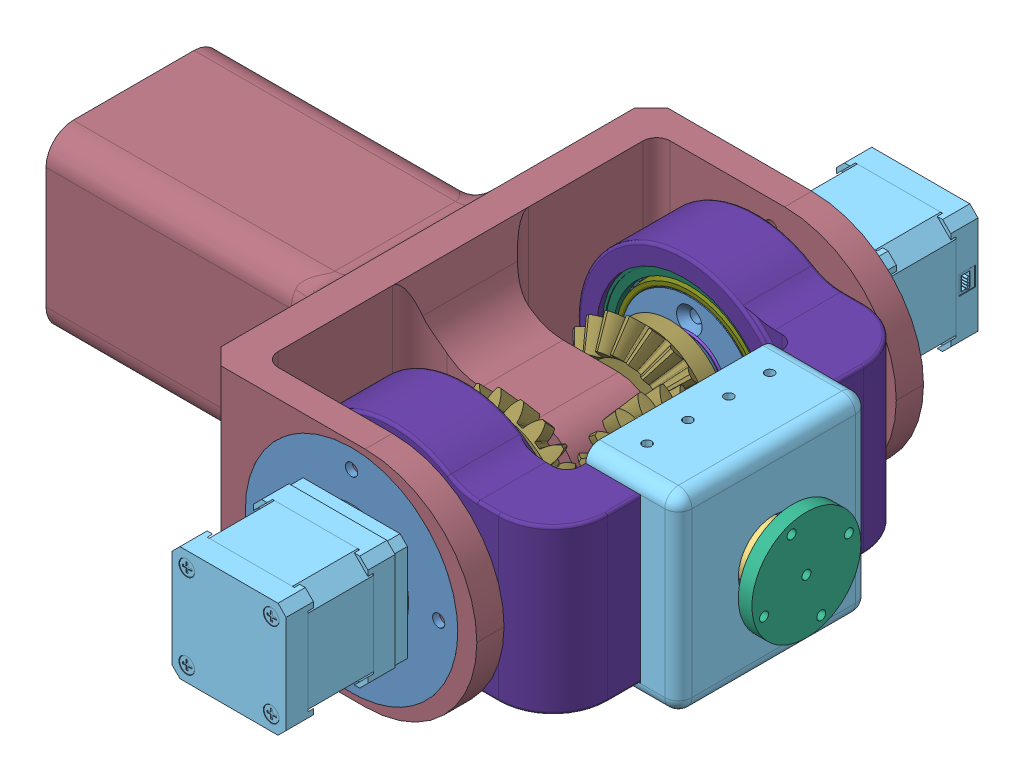
SolidWorks assembly Wrist assembly v3, configuration Default. Lengths in mm.
Overall size (247 82 254).
259 component instances, 28 part files, 61 mates.
Components (placement in the parent):
- Motor sleeve-1: Motor sleeve [Default] at (57.5488 50.2907 113.4481) x (0 0 -1) z (1 0 0) size (40 78 78)
- Motor sleeve-2: Motor sleeve [Default] at (57.5488 50.2907 -50.5519) x (0 0 1) z (-1 0 0) size (40 78 78)
- HK_1412-1: HK_1412 [Default] at (57.5488 50.2907 46.4481) x (0 0 -1) z (0.911021 -0.412359 0) size (12 20 20)
  - HK_1412_3-1: HK_1412_3 [Default] x (1 0 0) z (0 -0.382683 0.92388) size (7.3 2 2)
  - HK_1412_3-2: HK_1412_3 [Default] x (1 0 0) z (0 -0.707107 0.707107) size (7.3 2 2)
  - HK_1412_3-3: HK_1412_3 [Default] x (1 0 0) z (0 -0.92388 0.382683) size (7.3 2 2)
  - HK_1412_3-4: HK_1412_3 [Default] x (1 0 0) z (0 -1 0) size (7.3 2 2)
  - HK_1412_3-5: HK_1412_3 [Default] x (1 0 0) z (0 -0.92388 -0.382683) size (7.3 2 2)
  - HK_1412_3-6: HK_1412_3 [Default] x (1 0 0) z (0 -0.707107 -0.707107) size (7.3 2 2)
  - HK_1412_3-7: HK_1412_3 [Default] x (1 0 0) z (0 -0.382683 -0.92388) size (7.3 2 2)
  - HK_1412_3-8: HK_1412_3 [Default] x (1 0 0) z (0 0 -1) size (7.3 2 2)
  - HK_1412_3-9: HK_1412_3 [Default] x (1 0 0) z (0 0.382683 -0.92388) size (7.3 2 2)
  - HK_1412_3-10: HK_1412_3 [Default] x (1 0 0) z (0 0.707107 -0.707107) size (7.3 2 2)
  - HK_1412_3-11: HK_1412_3 [Default] x (1 0 0) z (0 0.92388 -0.382683) size (7.3 2 2)
  - HK_1412_3-12: HK_1412_3 [Default] x (1 0 0) z (0 1 0) size (7.3 2 2)
  - HK_1412_3-13: HK_1412_3 [Default] x (1 0 0) z (0 0.92388 0.382683) size (7.3 2 2)
  - HK_1412_3-14: HK_1412_3 [Default] x (1 0 0) z (0 0.707107 0.707107) size (7.3 2 2)
  - HK_1412_3-15: HK_1412_3 [Default] x (1 0 0) z (0 0.382683 0.92388) size (7.3 2 2)
  - HK_1412_3-16: HK_1412_3 [Default] at origin size (7.3 2 2)
  - HK_1412_20-1: HK_1412_20 [Default] x (1 0 0) z (0 -0.382683 0.92388) size (7.3 2 2)
  - HK_1412_20-2: HK_1412_20 [Default] x (1 0 0) z (0 -0.707107 0.707107) size (7.3 2 2)
  - HK_1412_20-3: HK_1412_20 [Default] x (1 0 0) z (0 -0.92388 0.382683) size (7.3 2 2)
  - HK_1412_20-4: HK_1412_20 [Default] x (1 0 0) z (0 -1 0) size (7.3 2 2)
  - HK_1412_20-5: HK_1412_20 [Default] x (1 0 0) z (0 -0.92388 -0.382683) size (7.3 2 2)
  - HK_1412_20-6: HK_1412_20 [Default] x (1 0 0) z (0 -0.707107 -0.707107) size (7.3 2 2)
  - HK_1412_20-7: HK_1412_20 [Default] x (1 0 0) z (0 -0.382683 -0.92388) size (7.3 2 2)
  - HK_1412_20-8: HK_1412_20 [Default] x (1 0 0) z (0 0 -1) size (7.3 2 2)
  - HK_1412_20-9: HK_1412_20 [Default] x (1 0 0) z (0 0.382683 -0.92388) size (7.3 2 2)
  - HK_1412_20-10: HK_1412_20 [Default] x (1 0 0) z (0 0.707107 -0.707107) size (7.3 2 2)
  - HK_1412_20-11: HK_1412_20 [Default] x (1 0 0) z (0 0.92388 -0.382683) size (7.3 2 2)
  - HK_1412_20-12: HK_1412_20 [Default] x (1 0 0) z (0 1 0) size (7.3 2 2)
  - HK_1412_20-13: HK_1412_20 [Default] x (1 0 0) z (0 0.92388 0.382683) size (7.3 2 2)
  - HK_1412_20-14: HK_1412_20 [Default] x (1 0 0) z (0 0.707107 0.707107) size (7.3 2 2)
  - HK_1412_20-15: HK_1412_20 [Default] x (1 0 0) z (0 0.382683 0.92388) size (7.3 2 2)
  - HK_1412_20-16: HK_1412_20 [Default] at origin size (7.3 2 2)
  - HK_1412_37-1: HK_1412_37 [Default] at origin size (12 20 20)
- HK_1412-2: HK_1412 [Default] at (57.5488 50.2907 28.4481) x (0 0 -1) z (0.122911 0.992418 0) size (12 20 20)
  - HK_1412_3-1: HK_1412_3 [Default] x (1 0 0) z (0 -0.382683 0.92388) size (7.3 2 2)
  - HK_1412_3-2: HK_1412_3 [Default] x (1 0 0) z (0 -0.707107 0.707107) size (7.3 2 2)
  - HK_1412_3-3: HK_1412_3 [Default] x (1 0 0) z (0 -0.92388 0.382683) size (7.3 2 2)
  - HK_1412_3-4: HK_1412_3 [Default] x (1 0 0) z (0 -1 0) size (7.3 2 2)
  - HK_1412_3-5: HK_1412_3 [Default] x (1 0 0) z (0 -0.92388 -0.382683) size (7.3 2 2)
  - HK_1412_3-6: HK_1412_3 [Default] x (1 0 0) z (0 -0.707107 -0.707107) size (7.3 2 2)
  - HK_1412_3-7: HK_1412_3 [Default] x (1 0 0) z (0 -0.382683 -0.92388) size (7.3 2 2)
  - HK_1412_3-8: HK_1412_3 [Default] x (1 0 0) z (0 0 -1) size (7.3 2 2)
  - HK_1412_3-9: HK_1412_3 [Default] x (1 0 0) z (0 0.382683 -0.92388) size (7.3 2 2)
  - HK_1412_3-10: HK_1412_3 [Default] x (1 0 0) z (0 0.707107 -0.707107) size (7.3 2 2)
  - HK_1412_3-11: HK_1412_3 [Default] x (1 0 0) z (0 0.92388 -0.382683) size (7.3 2 2)
  - HK_1412_3-12: HK_1412_3 [Default] x (1 0 0) z (0 1 0) size (7.3 2 2)
  - HK_1412_3-13: HK_1412_3 [Default] x (1 0 0) z (0 0.92388 0.382683) size (7.3 2 2)
  - HK_1412_3-14: HK_1412_3 [Default] x (1 0 0) z (0 0.707107 0.707107) size (7.3 2 2)
  - HK_1412_3-15: HK_1412_3 [Default] x (1 0 0) z (0 0.382683 0.92388) size (7.3 2 2)
  - HK_1412_3-16: HK_1412_3 [Default] at origin size (7.3 2 2)
  - HK_1412_20-1: HK_1412_20 [Default] x (1 0 0) z (0 -0.382683 0.92388) size (7.3 2 2)
  - HK_1412_20-2: HK_1412_20 [Default] x (1 0 0) z (0 -0.707107 0.707107) size (7.3 2 2)
  - HK_1412_20-3: HK_1412_20 [Default] x (1 0 0) z (0 -0.92388 0.382683) size (7.3 2 2)
  - HK_1412_20-4: HK_1412_20 [Default] x (1 0 0) z (0 -1 0) size (7.3 2 2)
  - HK_1412_20-5: HK_1412_20 [Default] x (1 0 0) z (0 -0.92388 -0.382683) size (7.3 2 2)
  - HK_1412_20-6: HK_1412_20 [Default] x (1 0 0) z (0 -0.707107 -0.707107) size (7.3 2 2)
  - HK_1412_20-7: HK_1412_20 [Default] x (1 0 0) z (0 -0.382683 -0.92388) size (7.3 2 2)
  - HK_1412_20-8: HK_1412_20 [Default] x (1 0 0) z (0 0 -1) size (7.3 2 2)
  - HK_1412_20-9: HK_1412_20 [Default] x (1 0 0) z (0 0.382683 -0.92388) size (7.3 2 2)
  - HK_1412_20-10: HK_1412_20 [Default] x (1 0 0) z (0 0.707107 -0.707107) size (7.3 2 2)
  - HK_1412_20-11: HK_1412_20 [Default] x (1 0 0) z (0 0.92388 -0.382683) size (7.3 2 2)
  - HK_1412_20-12: HK_1412_20 [Default] x (1 0 0) z (0 1 0) size (7.3 2 2)
  - HK_1412_20-13: HK_1412_20 [Default] x (1 0 0) z (0 0.92388 0.382683) size (7.3 2 2)
  - HK_1412_20-14: HK_1412_20 [Default] x (1 0 0) z (0 0.707107 0.707107) size (7.3 2 2)
  - HK_1412_20-15: HK_1412_20 [Default] x (1 0 0) z (0 0.382683 0.92388) size (7.3 2 2)
  - HK_1412_20-16: HK_1412_20 [Default] at origin size (7.3 2 2)
  - HK_1412_37-1: HK_1412_37 [Default] at origin size (12 20 20)
- 17HS15-1684D-HG10-AR3-2: 17HS15-1684D-HG10-AR3 [Default] at (57.5488 50.2907 -55.5519) size (42.88 42 103.5)
- 17HS15-1684D-HG10-AR3-3: 17HS15-1684D-HG10-AR3 [Default] at (57.5488 50.2907 118.4481) x (-1 0 0) z (0 0 -1) size (42.88 42 103.5)
- shaft-1: shaft [Default] at (57.5488 50.2907 -12.0519) x (0 0 1) z (0.017885 0.99984 0) size (42 17 17)
- shaft-2: shaft [Default] at (57.5488 50.2907 74.9481) x (0 0 -1) z (-0.597351 0.80198 0) size (42 17 17)
- AXK_1528___AS_1528___AS_1528-2: AXK_1528___AS_1528___AS_1528 [Default] at (57.5488 50.2907 71.4481) x (0 0 -1) z (0.812919 0.582377 0) size (4 28 28)
  - AXK_1528___AS_1528___AS_1528_3-1: AXK_1528___AS_1528___AS_1528_3 [Default] x (1 0 0) z (0 -0.309017 0.951057) size (2 5 2)
  - AXK_1528___AS_1528___AS_1528_3-2: AXK_1528___AS_1528___AS_1528_3 [Default] x (1 0 0) z (0 -0.587785 0.809017) size (2 5 2)
  - AXK_1528___AS_1528___AS_1528_3-3: AXK_1528___AS_1528___AS_1528_3 [Default] x (1 0 0) z (0 -0.809017 0.587785) size (2 5 2)
  - AXK_1528___AS_1528___AS_1528_3-4: AXK_1528___AS_1528___AS_1528_3 [Default] x (1 0 0) z (0 -0.951057 0.309017) size (2 5 2)
  - AXK_1528___AS_1528___AS_1528_3-5: AXK_1528___AS_1528___AS_1528_3 [Default] x (1 0 0) z (0 -1 0) size (2 5 2)
  - AXK_1528___AS_1528___AS_1528_3-6: AXK_1528___AS_1528___AS_1528_3 [Default] x (1 0 0) z (0 -0.951057 -0.309017) size (2 5 2)
  - AXK_1528___AS_1528___AS_1528_3-7: AXK_1528___AS_1528___AS_1528_3 [Default] x (1 0 0) z (0 -0.809017 -0.587785) size (2 5 2)
  - AXK_1528___AS_1528___AS_1528_3-8: AXK_1528___AS_1528___AS_1528_3 [Default] x (1 0 0) z (0 -0.587785 -0.809017) size (2 5 2)
  - AXK_1528___AS_1528___AS_1528_3-9: AXK_1528___AS_1528___AS_1528_3 [Default] x (1 0 0) z (0 -0.309017 -0.951057) size (2 5 2)
  - AXK_1528___AS_1528___AS_1528_3-10: AXK_1528___AS_1528___AS_1528_3 [Default] x (1 0 0) z (0 0 -1) size (2 5 2)
  - AXK_1528___AS_1528___AS_1528_3-11: AXK_1528___AS_1528___AS_1528_3 [Default] x (1 0 0) z (0 0.309017 -0.951057) size (2 5 2)
  - AXK_1528___AS_1528___AS_1528_3-12: AXK_1528___AS_1528___AS_1528_3 [Default] x (1 0 0) z (0 0.587785 -0.809017) size (2 5 2)
  - AXK_1528___AS_1528___AS_1528_3-13: AXK_1528___AS_1528___AS_1528_3 [Default] x (1 0 0) z (0 0.809017 -0.587785) size (2 5 2)
  - AXK_1528___AS_1528___AS_1528_3-14: AXK_1528___AS_1528___AS_1528_3 [Default] x (1 0 0) z (0 0.951057 -0.309017) size (2 5 2)
  - AXK_1528___AS_1528___AS_1528_3-15: AXK_1528___AS_1528___AS_1528_3 [Default] x (1 0 0) z (0 1 0) size (2 5 2)
  - AXK_1528___AS_1528___AS_1528_3-16: AXK_1528___AS_1528___AS_1528_3 [Default] x (1 0 0) z (0 0.951057 0.309017) size (2 5 2)
  - AXK_1528___AS_1528___AS_1528_3-17: AXK_1528___AS_1528___AS_1528_3 [Default] x (1 0 0) z (0 0.809017 0.587785) size (2 5 2)
  - AXK_1528___AS_1528___AS_1528_3-18: AXK_1528___AS_1528___AS_1528_3 [Default] x (1 0 0) z (0 0.587785 0.809017) size (2 5 2)
  - AXK_1528___AS_1528___AS_1528_3-19: AXK_1528___AS_1528___AS_1528_3 [Default] x (1 0 0) z (0 0.309017 0.951057) size (2 5 2)
  - AXK_1528___AS_1528___AS_1528_3-20: AXK_1528___AS_1528___AS_1528_3 [Default] at origin size (2 5 2)
  - AXK_1528___AS_1528___AS_1528_24-1: AXK_1528___AS_1528___AS_1528_24 [Default] at origin size (1 28 28)
  - AXK_1528___AS_1528___AS_1528_26-1: AXK_1528___AS_1528___AS_1528_26 [Default] at origin size (1 28 28)
  - AXK_1528___AS_1528___AS_1528_28-1: AXK_1528___AS_1528___AS_1528_28 [Default] at origin size (1.6 28 28)
- 2mm spacer-1: 2mm spacer [Default] at (57.5488 50.2907 66.4481) x (0.999741 0.022777 0) z (0 0 1) size (28 28 1.5)
- straight miter gear_am-1: straight miter gear_am [A 1C 4MYKW25020] at (57.5488 50.2907 59.074) x (0 0 -1) z (0.597351 -0.80198 0) size (19.66 53.34 53.34)
- AXK_1528___AS_1528___AS_1528-3: AXK_1528___AS_1528___AS_1528 [Default] at (57.5488 50.2907 -8.5519) x (0 0 -1) z (0.999526 -0.030788 0) size (4 28 28)
  - AXK_1528___AS_1528___AS_1528_3-1: AXK_1528___AS_1528___AS_1528_3 [Default] x (1 0 0) z (0 -0.309017 0.951057) size (2 5 2)
  - AXK_1528___AS_1528___AS_1528_3-2: AXK_1528___AS_1528___AS_1528_3 [Default] x (1 0 0) z (0 -0.587785 0.809017) size (2 5 2)
  - AXK_1528___AS_1528___AS_1528_3-3: AXK_1528___AS_1528___AS_1528_3 [Default] x (1 0 0) z (0 -0.809017 0.587785) size (2 5 2)
  - AXK_1528___AS_1528___AS_1528_3-4: AXK_1528___AS_1528___AS_1528_3 [Default] x (1 0 0) z (0 -0.951057 0.309017) size (2 5 2)
  - AXK_1528___AS_1528___AS_1528_3-5: AXK_1528___AS_1528___AS_1528_3 [Default] x (1 0 0) z (0 -1 0) size (2 5 2)
  - AXK_1528___AS_1528___AS_1528_3-6: AXK_1528___AS_1528___AS_1528_3 [Default] x (1 0 0) z (0 -0.951057 -0.309017) size (2 5 2)
  - AXK_1528___AS_1528___AS_1528_3-7: AXK_1528___AS_1528___AS_1528_3 [Default] x (1 0 0) z (0 -0.809017 -0.587785) size (2 5 2)
  - AXK_1528___AS_1528___AS_1528_3-8: AXK_1528___AS_1528___AS_1528_3 [Default] x (1 0 0) z (0 -0.587785 -0.809017) size (2 5 2)
  - AXK_1528___AS_1528___AS_1528_3-9: AXK_1528___AS_1528___AS_1528_3 [Default] x (1 0 0) z (0 -0.309017 -0.951057) size (2 5 2)
  - AXK_1528___AS_1528___AS_1528_3-10: AXK_1528___AS_1528___AS_1528_3 [Default] x (1 0 0) z (0 0 -1) size (2 5 2)
  - AXK_1528___AS_1528___AS_1528_3-11: AXK_1528___AS_1528___AS_1528_3 [Default] x (1 0 0) z (0 0.309017 -0.951057) size (2 5 2)
  - AXK_1528___AS_1528___AS_1528_3-12: AXK_1528___AS_1528___AS_1528_3 [Default] x (1 0 0) z (0 0.587785 -0.809017) size (2 5 2)
  - AXK_1528___AS_1528___AS_1528_3-13: AXK_1528___AS_1528___AS_1528_3 [Default] x (1 0 0) z (0 0.809017 -0.587785) size (2 5 2)
  - AXK_1528___AS_1528___AS_1528_3-14: AXK_1528___AS_1528___AS_1528_3 [Default] x (1 0 0) z (0 0.951057 -0.309017) size (2 5 2)
  - AXK_1528___AS_1528___AS_1528_3-15: AXK_1528___AS_1528___AS_1528_3 [Default] x (1 0 0) z (0 1 0) size (2 5 2)
  - AXK_1528___AS_1528___AS_1528_3-16: AXK_1528___AS_1528___AS_1528_3 [Default] x (1 0 0) z (0 0.951057 0.309017) size (2 5 2)
  - AXK_1528___AS_1528___AS_1528_3-17: AXK_1528___AS_1528___AS_1528_3 [Default] x (1 0 0) z (0 0.809017 0.587785) size (2 5 2)
  - AXK_1528___AS_1528___AS_1528_3-18: AXK_1528___AS_1528___AS_1528_3 [Default] x (1 0 0) z (0 0.587785 0.809017) size (2 5 2)
  - AXK_1528___AS_1528___AS_1528_3-19: AXK_1528___AS_1528___AS_1528_3 [Default] x (1 0 0) z (0 0.309017 0.951057) size (2 5 2)
  - AXK_1528___AS_1528___AS_1528_3-20: AXK_1528___AS_1528___AS_1528_3 [Default] at origin size (2 5 2)
  - AXK_1528___AS_1528___AS_1528_24-1: AXK_1528___AS_1528___AS_1528_24 [Default] at origin size (1 28 28)
  - AXK_1528___AS_1528___AS_1528_26-1: AXK_1528___AS_1528___AS_1528_26 [Default] at origin size (1 28 28)
  - AXK_1528___AS_1528___AS_1528_28-1: AXK_1528___AS_1528___AS_1528_28 [Default] at origin size (1.6 28 28)
- 2mm spacer-2: 2mm spacer [Default] at (57.5488 50.2907 -5.0519) x (0.999526 -0.030788 0) z (0 0 1) size (28 28 1.5)
- straight miter gear_am-2: straight miter gear_am [A 1C 4MYKW25020] at (57.5488 50.2907 3.8222) x (0 0 1) z (-0.017885 -0.99984 0) size (19.66 53.34 53.34)
- Wrist input frame_combined-2: Wrist input frame_combined [Default] at (-20.9706 -62.2225 152.6176) x (-1 0 0) z (0 0 -1) size (208 82 164)
- NKI_50_25-1: NKI_50_25 [Default] at (57.5488 50.2907 -10.5519) x (0 0 -1) z (0.995738 -0.092229 0) size (25 68.42 68)
  - NKI_50_25_37-1: NKI_50_25_37 [Default] x (1 0 0) z (0 -0.189251 0.981929) size (18.8 3.5 3.5)
  - NKI_50_25_37-2: NKI_50_25_37 [Default] x (1 0 0) z (0 -0.371662 0.928368) size (18.8 3.5 3.5)
  - NKI_50_25_37-3: NKI_50_25_37 [Default] x (1 0 0) z (0 -0.540641 0.841254) size (18.8 3.5 3.5)
  - NKI_50_25_37-4: NKI_50_25_37 [Default] x (1 0 0) z (0 -0.690079 0.723734) size (18.8 3.5 3.5)
  - NKI_50_25_37-5: NKI_50_25_37 [Default] x (1 0 0) z (0 -0.814576 0.580057) size (18.8 3.5 3.5)
  - NKI_50_25_37-6: NKI_50_25_37 [Default] x (1 0 0) z (0 -0.909632 0.415415) size (18.8 3.5 3.5)
  - NKI_50_25_37-7: NKI_50_25_37 [Default] x (1 0 0) z (0 -0.971812 0.235759) size (18.8 3.5 3.5)
  - NKI_50_25_37-8: NKI_50_25_37 [Default] x (1 0 0) z (0 -0.998867 0.047582) size (18.8 3.5 3.5)
  - NKI_50_25_37-9: NKI_50_25_37 [Default] x (1 0 0) z (0 -0.989821 -0.142315) size (18.8 3.5 3.5)
  - NKI_50_25_37-10: NKI_50_25_37 [Default] x (1 0 0) z (0 -0.945001 -0.327068) size (18.8 3.5 3.5)
  - NKI_50_25_37-11: NKI_50_25_37 [Default] x (1 0 0) z (0 -0.866025 -0.5) size (18.8 3.5 3.5)
  - NKI_50_25_37-12: NKI_50_25_37 [Default] x (1 0 0) z (0 -0.75575 -0.654861) size (18.8 3.5 3.5)
  - NKI_50_25_37-13: NKI_50_25_37 [Default] x (1 0 0) z (0 -0.618159 -0.786053) size (18.8 3.5 3.5)
  - NKI_50_25_37-14: NKI_50_25_37 [Default] x (1 0 0) z (0 -0.458227 -0.888835) size (18.8 3.5 3.5)
  - NKI_50_25_37-15: NKI_50_25_37 [Default] x (1 0 0) z (0 -0.281733 -0.959493) size (18.8 3.5 3.5)
  - NKI_50_25_37-16: NKI_50_25_37 [Default] x (1 0 0) z (0 -0.095056 -0.995472) size (18.8 3.5 3.5)
  - NKI_50_25_37-17: NKI_50_25_37 [Default] x (1 0 0) z (0 0.095056 -0.995472) size (18.8 3.5 3.5)
  - NKI_50_25_37-18: NKI_50_25_37 [Default] x (1 0 0) z (0 0.281733 -0.959493) size (18.8 3.5 3.5)
  - NKI_50_25_37-19: NKI_50_25_37 [Default] x (1 0 0) z (0 0.458227 -0.888835) size (18.8 3.5 3.5)
  - NKI_50_25_37-20: NKI_50_25_37 [Default] x (1 0 0) z (0 0.618159 -0.786053) size (18.8 3.5 3.5)
  - NKI_50_25_37-21: NKI_50_25_37 [Default] x (1 0 0) z (0 0.75575 -0.654861) size (18.8 3.5 3.5)
  - NKI_50_25_37-22: NKI_50_25_37 [Default] x (1 0 0) z (0 0.866025 -0.5) size (18.8 3.5 3.5)
  - NKI_50_25_37-23: NKI_50_25_37 [Default] x (1 0 0) z (0 0.945001 -0.327068) size (18.8 3.5 3.5)
  - NKI_50_25_37-24: NKI_50_25_37 [Default] x (1 0 0) z (0 0.989821 -0.142315) size (18.8 3.5 3.5)
  - NKI_50_25_37-25: NKI_50_25_37 [Default] x (1 0 0) z (0 0.998867 0.047582) size (18.8 3.5 3.5)
  - NKI_50_25_37-26: NKI_50_25_37 [Default] x (1 0 0) z (0 0.971812 0.235759) size (18.8 3.5 3.5)
  - NKI_50_25_37-27: NKI_50_25_37 [Default] x (1 0 0) z (0 0.909632 0.415415) size (18.8 3.5 3.5)
  - NKI_50_25_37-28: NKI_50_25_37 [Default] x (1 0 0) z (0 0.814576 0.580057) size (18.8 3.5 3.5)
  - NKI_50_25_37-29: NKI_50_25_37 [Default] x (1 0 0) z (0 0.690079 0.723734) size (18.8 3.5 3.5)
  - NKI_50_25_37-30: NKI_50_25_37 [Default] x (1 0 0) z (0 0.540641 0.841254) size (18.8 3.5 3.5)
  - NKI_50_25_37-31: NKI_50_25_37 [Default] x (1 0 0) z (0 0.371662 0.928368) size (18.8 3.5 3.5)
  - NKI_50_25_37-32: NKI_50_25_37 [Default] x (1 0 0) z (0 0.189251 0.981929) size (18.8 3.5 3.5)
  - NKI_50_25_37-33: NKI_50_25_37 [Default] at origin size (18.8 3.5 3.5)
  - NKI_50_25_71-1: NKI_50_25_71 [Default] at origin size (25 68.42 68)
  - NKI_50_25_73-1: NKI_50_25_73 [Default] at origin size (25 55 55)
- NKI_50_25-2: NKI_50_25 [Default] at (57.5488 50.2907 98.4481) x (0 0 -1) z (0.982967 -0.183783 0) size (25 68.42 68)
  - NKI_50_25_37-1: NKI_50_25_37 [Default] x (1 0 0) z (0 -0.189251 0.981929) size (18.8 3.5 3.5)
  - NKI_50_25_37-2: NKI_50_25_37 [Default] x (1 0 0) z (0 -0.371662 0.928368) size (18.8 3.5 3.5)
  - NKI_50_25_37-3: NKI_50_25_37 [Default] x (1 0 0) z (0 -0.540641 0.841254) size (18.8 3.5 3.5)
  - NKI_50_25_37-4: NKI_50_25_37 [Default] x (1 0 0) z (0 -0.690079 0.723734) size (18.8 3.5 3.5)
  - NKI_50_25_37-5: NKI_50_25_37 [Default] x (1 0 0) z (0 -0.814576 0.580057) size (18.8 3.5 3.5)
  - NKI_50_25_37-6: NKI_50_25_37 [Default] x (1 0 0) z (0 -0.909632 0.415415) size (18.8 3.5 3.5)
  - NKI_50_25_37-7: NKI_50_25_37 [Default] x (1 0 0) z (0 -0.971812 0.235759) size (18.8 3.5 3.5)
  - NKI_50_25_37-8: NKI_50_25_37 [Default] x (1 0 0) z (0 -0.998867 0.047582) size (18.8 3.5 3.5)
  - NKI_50_25_37-9: NKI_50_25_37 [Default] x (1 0 0) z (0 -0.989821 -0.142315) size (18.8 3.5 3.5)
  - NKI_50_25_37-10: NKI_50_25_37 [Default] x (1 0 0) z (0 -0.945001 -0.327068) size (18.8 3.5 3.5)
  - NKI_50_25_37-11: NKI_50_25_37 [Default] x (1 0 0) z (0 -0.866025 -0.5) size (18.8 3.5 3.5)
  - NKI_50_25_37-12: NKI_50_25_37 [Default] x (1 0 0) z (0 -0.75575 -0.654861) size (18.8 3.5 3.5)
  - NKI_50_25_37-13: NKI_50_25_37 [Default] x (1 0 0) z (0 -0.618159 -0.786053) size (18.8 3.5 3.5)
  - NKI_50_25_37-14: NKI_50_25_37 [Default] x (1 0 0) z (0 -0.458227 -0.888835) size (18.8 3.5 3.5)
  - NKI_50_25_37-15: NKI_50_25_37 [Default] x (1 0 0) z (0 -0.281733 -0.959493) size (18.8 3.5 3.5)
  - NKI_50_25_37-16: NKI_50_25_37 [Default] x (1 0 0) z (0 -0.095056 -0.995472) size (18.8 3.5 3.5)
  - NKI_50_25_37-17: NKI_50_25_37 [Default] x (1 0 0) z (0 0.095056 -0.995472) size (18.8 3.5 3.5)
  - NKI_50_25_37-18: NKI_50_25_37 [Default] x (1 0 0) z (0 0.281733 -0.959493) size (18.8 3.5 3.5)
  - NKI_50_25_37-19: NKI_50_25_37 [Default] x (1 0 0) z (0 0.458227 -0.888835) size (18.8 3.5 3.5)
  - NKI_50_25_37-20: NKI_50_25_37 [Default] x (1 0 0) z (0 0.618159 -0.786053) size (18.8 3.5 3.5)
  - NKI_50_25_37-21: NKI_50_25_37 [Default] x (1 0 0) z (0 0.75575 -0.654861) size (18.8 3.5 3.5)
  - NKI_50_25_37-22: NKI_50_25_37 [Default] x (1 0 0) z (0 0.866025 -0.5) size (18.8 3.5 3.5)
  - NKI_50_25_37-23: NKI_50_25_37 [Default] x (1 0 0) z (0 0.945001 -0.327068) size (18.8 3.5 3.5)
  - NKI_50_25_37-24: NKI_50_25_37 [Default] x (1 0 0) z (0 0.989821 -0.142315) size (18.8 3.5 3.5)
  - NKI_50_25_37-25: NKI_50_25_37 [Default] x (1 0 0) z (0 0.998867 0.047582) size (18.8 3.5 3.5)
  - NKI_50_25_37-26: NKI_50_25_37 [Default] x (1 0 0) z (0 0.971812 0.235759) size (18.8 3.5 3.5)
  - NKI_50_25_37-27: NKI_50_25_37 [Default] x (1 0 0) z (0 0.909632 0.415415) size (18.8 3.5 3.5)
  - NKI_50_25_37-28: NKI_50_25_37 [Default] x (1 0 0) z (0 0.814576 0.580057) size (18.8 3.5 3.5)
  - NKI_50_25_37-29: NKI_50_25_37 [Default] x (1 0 0) z (0 0.690079 0.723734) size (18.8 3.5 3.5)
  - NKI_50_25_37-30: NKI_50_25_37 [Default] x (1 0 0) z (0 0.540641 0.841254) size (18.8 3.5 3.5)
  - NKI_50_25_37-31: NKI_50_25_37 [Default] x (1 0 0) z (0 0.371662 0.928368) size (18.8 3.5 3.5)
  - NKI_50_25_37-32: NKI_50_25_37 [Default] x (1 0 0) z (0 0.189251 0.981929) size (18.8 3.5 3.5)
  - NKI_50_25_37-33: NKI_50_25_37 [Default] at origin size (18.8 3.5 3.5)
  - NKI_50_25_71-1: NKI_50_25_71 [Default] at origin size (25 68.42 68)
  - NKI_50_25_73-1: NKI_50_25_73 [Default] at origin size (25 55 55)
- Wrist output frame-1: Wrist output frame [Default] at (57.5488 50.2907 98.4481) x (0 0 -1) z (0 -1 0) size (134 102 78)
- 7203_BEY-3: 7203_BEY [Default] at (108.5488 50.2907 31.4481) x (-1 0 0) z (0 -0.984874 -0.173274) size (12 40 40)
  - 7203_BEY_3-1: 7203_BEY_3 [Default] x (1 0 0) z (0 -0.587785 0.809017) size (7.14 7.14 7.14)
  - 7203_BEY_3-2: 7203_BEY_3 [Default] x (1 0 0) z (0 -0.951057 0.309017) size (7.14 7.14 7.14)
  - 7203_BEY_3-3: 7203_BEY_3 [Default] x (1 0 0) z (0 -0.951057 -0.309017) size (7.14 7.14 7.14)
  - 7203_BEY_3-4: 7203_BEY_3 [Default] x (1 0 0) z (0 -0.587785 -0.809017) size (7.14 7.14 7.14)
  - 7203_BEY_3-5: 7203_BEY_3 [Default] x (1 0 0) z (0 0 -1) size (7.14 7.14 7.14)
  - 7203_BEY_3-6: 7203_BEY_3 [Default] x (1 0 0) z (0 0.587785 -0.809017) size (7.14 7.14 7.14)
  - 7203_BEY_3-7: 7203_BEY_3 [Default] x (1 0 0) z (0 0.951057 -0.309017) size (7.14 7.14 7.14)
  - 7203_BEY_3-8: 7203_BEY_3 [Default] x (1 0 0) z (0 0.951057 0.309017) size (7.14 7.14 7.14)
  - 7203_BEY_3-9: 7203_BEY_3 [Default] x (1 0 0) z (0 0.587785 0.809017) size (7.14 7.14 7.14)
  - 7203_BEY_3-10: 7203_BEY_3 [Default] at origin size (7.14 7.14 7.14)
  - 7203_BEY_14-1: 7203_BEY_14 [Default] at origin size (12 40 40)
  - 7203_BEY_16-1: 7203_BEY_16 [Default] at origin size (12 26.25 26.25)
- 7203_BEY-4: 7203_BEY [Default] at (108.5488 50.2907 31.4481) x (1 0 0) z (0 0.327595 0.944818) size (12 40 40)
  - 7203_BEY_3-1: 7203_BEY_3 [Default] x (1 0 0) z (0 -0.587785 0.809017) size (7.14 7.14 7.14)
  - 7203_BEY_3-2: 7203_BEY_3 [Default] x (1 0 0) z (0 -0.951057 0.309017) size (7.14 7.14 7.14)
  - 7203_BEY_3-3: 7203_BEY_3 [Default] x (1 0 0) z (0 -0.951057 -0.309017) size (7.14 7.14 7.14)
  - 7203_BEY_3-4: 7203_BEY_3 [Default] x (1 0 0) z (0 -0.587785 -0.809017) size (7.14 7.14 7.14)
  - 7203_BEY_3-5: 7203_BEY_3 [Default] x (1 0 0) z (0 0 -1) size (7.14 7.14 7.14)
  - 7203_BEY_3-6: 7203_BEY_3 [Default] x (1 0 0) z (0 0.587785 -0.809017) size (7.14 7.14 7.14)
  - 7203_BEY_3-7: 7203_BEY_3 [Default] x (1 0 0) z (0 0.951057 -0.309017) size (7.14 7.14 7.14)
  - 7203_BEY_3-8: 7203_BEY_3 [Default] x (1 0 0) z (0 0.951057 0.309017) size (7.14 7.14 7.14)
  - 7203_BEY_3-9: 7203_BEY_3 [Default] x (1 0 0) z (0 0.587785 0.809017) size (7.14 7.14 7.14)
  - 7203_BEY_3-10: 7203_BEY_3 [Default] at origin size (7.14 7.14 7.14)
  - 7203_BEY_14-1: 7203_BEY_14 [Default] at origin size (12 40 40)
  - 7203_BEY_16-1: 7203_BEY_16 [Default] at origin size (12 26.25 26.25)
- Output shaft-1: Output shaft [Default] at (75.5488 50.2907 31.4481) x (0 0.330033 -0.94397) z (1 0 0) size (22.5 22.5 62)
- 4mm spacer-1: 4mm spacer [Default] at (92.5488 50.2907 31.4481) x (0 -0.609252 -0.792977) z (1 0 0) size (26 26 4)
- straight miter gear_am-3: straight miter gear_am [A 1C 4MYKW25020] at (85.1747 50.2907 31.4481) x (-1 0 0) z (0 -0.883146 0.469098) size (19.66 53.34 53.34)
- End effector mounting fixture-2: End effector mounting fixture [Default] at (96.5488 50.2907 -3.5519) size (34 70 70)
- End effector mount-1: End effector mount [Default] at (132.5488 50.2907 31.4481) x (0 -0.330033 0.94397) z (1 0 0) size (40 40 10)
- AXK_2035___AS_2035___AS_2035-1: AXK_2035___AS_2035___AS_2035 [Default] at (124.5488 50.2907 31.4481) x (1 0 0) z (0 -0.248514 0.968628) size (4 35 35)
  - AXK_2035___AS_2035___AS_2035_3-1: AXK_2035___AS_2035___AS_2035_3 [Default] x (1 0 0) z (0 -0.258819 0.965926) size (2 6 2)
  - AXK_2035___AS_2035___AS_2035_3-2: AXK_2035___AS_2035___AS_2035_3 [Default] x (1 0 0) z (0 -0.5 0.866025) size (2 6 2)
  - AXK_2035___AS_2035___AS_2035_3-3: AXK_2035___AS_2035___AS_2035_3 [Default] x (1 0 0) z (0 -0.707107 0.707107) size (2 6 2)
  - AXK_2035___AS_2035___AS_2035_3-4: AXK_2035___AS_2035___AS_2035_3 [Default] x (1 0 0) z (0 -0.866025 0.5) size (2 6 2)
  - AXK_2035___AS_2035___AS_2035_3-5: AXK_2035___AS_2035___AS_2035_3 [Default] x (1 0 0) z (0 -0.965926 0.258819) size (2 6 2)
  - AXK_2035___AS_2035___AS_2035_3-6: AXK_2035___AS_2035___AS_2035_3 [Default] x (1 0 0) z (0 -1 0) size (2 6 2)
  - AXK_2035___AS_2035___AS_2035_3-7: AXK_2035___AS_2035___AS_2035_3 [Default] x (1 0 0) z (0 -0.965926 -0.258819) size (2 6 2)
  - AXK_2035___AS_2035___AS_2035_3-8: AXK_2035___AS_2035___AS_2035_3 [Default] x (1 0 0) z (0 -0.866025 -0.5) size (2 6 2)
  - AXK_2035___AS_2035___AS_2035_3-9: AXK_2035___AS_2035___AS_2035_3 [Default] x (1 0 0) z (0 -0.707107 -0.707107) size (2 6 2)
  - AXK_2035___AS_2035___AS_2035_3-10: AXK_2035___AS_2035___AS_2035_3 [Default] x (1 0 0) z (0 -0.5 -0.866025) size (2 6 2)
  - AXK_2035___AS_2035___AS_2035_3-11: AXK_2035___AS_2035___AS_2035_3 [Default] x (1 0 0) z (0 -0.258819 -0.965926) size (2 6 2)
  - AXK_2035___AS_2035___AS_2035_3-12: AXK_2035___AS_2035___AS_2035_3 [Default] x (1 0 0) z (0 0 -1) size (2 6 2)
  - AXK_2035___AS_2035___AS_2035_3-13: AXK_2035___AS_2035___AS_2035_3 [Default] x (1 0 0) z (0 0.258819 -0.965926) size (2 6 2)
  - AXK_2035___AS_2035___AS_2035_3-14: AXK_2035___AS_2035___AS_2035_3 [Default] x (1 0 0) z (0 0.5 -0.866025) size (2 6 2)
  - AXK_2035___AS_2035___AS_2035_3-15: AXK_2035___AS_2035___AS_2035_3 [Default] x (1 0 0) z (0 0.707107 -0.707107) size (2 6 2)
  - AXK_2035___AS_2035___AS_2035_3-16: AXK_2035___AS_2035___AS_2035_3 [Default] x (1 0 0) z (0 0.866025 -0.5) size (2 6 2)
  - AXK_2035___AS_2035___AS_2035_3-17: AXK_2035___AS_2035___AS_2035_3 [Default] x (1 0 0) z (0 0.965926 -0.258819) size (2 6 2)
  - AXK_2035___AS_2035___AS_2035_3-18: AXK_2035___AS_2035___AS_2035_3 [Default] x (1 0 0) z (0 1 0) size (2 6 2)
  - AXK_2035___AS_2035___AS_2035_3-19: AXK_2035___AS_2035___AS_2035_3 [Default] x (1 0 0) z (0 0.965926 0.258819) size (2 6 2)
  - AXK_2035___AS_2035___AS_2035_3-20: AXK_2035___AS_2035___AS_2035_3 [Default] x (1 0 0) z (0 0.866025 0.5) size (2 6 2)
  - AXK_2035___AS_2035___AS_2035_3-21: AXK_2035___AS_2035___AS_2035_3 [Default] x (1 0 0) z (0 0.707107 0.707107) size (2 6 2)
  - AXK_2035___AS_2035___AS_2035_3-22: AXK_2035___AS_2035___AS_2035_3 [Default] x (1 0 0) z (0 0.5 0.866025) size (2 6 2)
  - AXK_2035___AS_2035___AS_2035_3-23: AXK_2035___AS_2035___AS_2035_3 [Default] x (1 0 0) z (0 0.258819 0.965926) size (2 6 2)
  - AXK_2035___AS_2035___AS_2035_3-24: AXK_2035___AS_2035___AS_2035_3 [Default] at origin size (2 6 2)
  - AXK_2035___AS_2035___AS_2035_28-1: AXK_2035___AS_2035___AS_2035_28 [Default] at origin size (1 35 35)
  - AXK_2035___AS_2035___AS_2035_30-1: AXK_2035___AS_2035___AS_2035_30 [Default] at origin size (1 35 35)
  - AXK_2035___AS_2035___AS_2035_32-1: AXK_2035___AS_2035___AS_2035_32 [Default] at origin size (1.6 35 35)
Mates (geometry in assembly coordinates):
- Concentric10: concentric aligned: cylinder of Motor sleeve-2 through (57.5488 50.2907 -114.6552) axis (0 0 -1) radius 21; cylinder of 17HS15-1684D-HG10-AR3-2 through (57.5488 50.2907 -15.5519) axis (0 0 -1) radius 21
- Concentric11: concentric aligned: cylinder of Motor sleeve-2 through (57.5488 67.7907 -10.5519) axis (0 0 1) radius 2.25; cylinder of 17HS15-1684D-HG10-AR3-2 through (57.5488 67.7907 -15.5519) axis (0 0 1) radius 2.25
- Concentric13: concentric aligned: cylinder of Motor sleeve-1 through (57.5488 50.2907 177.5515) axis (0 0 1) radius 21; cylinder of 17HS15-1684D-HG10-AR3-3 through (57.5488 50.2907 78.4481) axis (0 0 1) radius 21
- Concentric16: concentric aligned: cylinder of Motor sleeve-1 through (57.5488 67.7907 73.4481) axis (0 0 -1) radius 2.25; circle of 17HS15-1684D-HG10-AR3-3
- Coincident5: coincident anti-aligned: plane of Motor sleeve-2 through (57.5488 71.2907 -15.5519) normal (0 0 -1); plane of 17HS15-1684D-HG10-AR3-2 through (57.5488 50.2907 -15.5519) normal (0 0 1)
- Coincident7: coincident anti-aligned: plane of Motor sleeve-1 through (57.5488 71.2907 78.4481) normal (0 0 1); plane of 17HS15-1684D-HG10-AR3-3 through (57.5488 50.2907 78.4481) normal (0 0 -1)
- Concentric17: concentric aligned: cylinder of 17HS15-1684D-HG10-AR3-2 through (57.5488 50.2907 -8.2519) axis (0 0 -1) radius 4; cylinder of shaft-1 through (57.5488 50.2907 29.9481) axis (0 0 -1) radius 4
- Distance2: distance = 1.5 mm anti-aligned: plane of 17HS15-1684D-HG10-AR3-2 through (57.5488 50.2907 -13.5519) normal (0 0 1); plane of shaft-1 through (57.5488 50.2907 -12.0519) normal (0 0 -1)
- Concentric18: concentric aligned: cylinder of 17HS15-1684D-HG10-AR3-3 through (57.5488 50.2907 71.1481) axis (0 0 1) radius 4; cylinder of shaft-2 through (57.5488 50.2907 32.9481) axis (0 0 1) radius 4
- Distance3: distance = 1.5 mm anti-aligned: plane of 17HS15-1684D-HG10-AR3-3 through (57.5488 50.2907 76.4481) normal (0 0 -1); plane of shaft-2 through (57.5488 50.2907 74.9481) normal (0 0 1)
- Concentric20: concentric anti-aligned: cylinder of shaft-2 through (57.5488 50.2907 69.9481) axis (0 0 1) radius 7.5; circle of AXK_1528___AS_1528___AS_1528-2/AXK_1528___AS_1528___AS_1528_24-1
- Coincident10: coincident anti-aligned: plane of Motor sleeve-1 through (57.5488 58.7907 73.4481) normal (0 0 -1); plane of AXK_1528___AS_1528___AS_1528-2/AXK_1528___AS_1528___AS_1528_26-1 through (49.3956 61.6715 73.4481) normal (0 0 1)
- Concentric21: concentric anti-aligned: cylinder of shaft-2 through (57.5488 50.2907 32.9481) axis (0 0 1) radius 7.5; cylinder of 2mm spacer-1 through (57.5488 50.2907 67.9481) axis (0 0 -1) radius 7
- Coincident11: coincident anti-aligned: plane of shaft-2 through (57.5488 50.2907 67.9481) normal (0 0 -1); plane of 2mm spacer-1 through (57.5488 50.2907 67.9481) normal (0 0 1)
- Concentric22: concentric aligned: cylinder of shaft-2 through (57.5488 50.2907 32.9481) axis (0 0 1) radius 7.5; cylinder of straight miter gear_am-1 through (57.5488 50.2907 24.074) axis (0 0 1) radius 7
- Parallel2: parallel anti-aligned: plane of shaft-2 through (61.4647 55.0777 65.9481) normal (0.80198 0.597351 0); plane of straight miter gear_am-1 through (66.5006 53.8411 24.074) normal (-0.80198 -0.597351 0)
- Coincident13: coincident anti-aligned: plane of 2mm spacer-1 through (57.5488 50.2907 66.4481) normal (0 0 -1); plane of straight miter gear_am-1 through (57.5488 50.2907 66.4481) normal (0 0 1)
- Concentric23: concentric anti-aligned: cylinder of shaft-1 through (57.5488 50.2907 -7.0519) axis (0 0 -1) radius 7.5; cylinder of AXK_1528___AS_1528___AS_1528-3/AXK_1528___AS_1528___AS_1528_28-1 through (57.5488 50.2907 -9.3519) axis (0 0 1) radius 7.5
- Coincident14: coincident anti-aligned: plane of Motor sleeve-2 through (57.5488 58.7907 -10.5519) normal (0 0 1); plane of AXK_1528___AS_1528___AS_1528-3/AXK_1528___AS_1528___AS_1528_24-1 through (57.7797 57.7871 -10.5519) normal (0 0 -1)
- Concentric241: concentric aligned: cylinder of shaft-1 through (57.5488 50.2907 29.9481) axis (0 0 -1) radius 7.5; cylinder of 2mm spacer-2 through (57.5488 50.2907 -3.5519) axis (0 0 -1) radius 14
- Coincident15: coincident anti-aligned: plane of shaft-1 through (57.5488 50.2907 -5.0519) normal (0 0 1); plane of 2mm spacer-2 through (57.5488 50.2907 -5.0519) normal (0 0 -1)
- Concentric25: concentric aligned: cylinder of shaft-1 through (57.5488 50.2907 29.9481) axis (0 0 -1) radius 7.5; cylinder of straight miter gear_am-2 through (57.5488 50.2907 38.8222) axis (0 0 -1) radius 7
- Parallel3: parallel anti-aligned: plane of shaft-1 through (51.5766 51.8977 -3.0519) normal (-0.99984 0.017885 0); plane of straight miter gear_am-2 through (48.2056 47.9574 38.8222) normal (0.99984 -0.017885 0)
- Coincident16: coincident anti-aligned: plane of 2mm spacer-2 through (57.5488 50.2907 -3.5519) normal (0 0 1); plane of straight miter gear_am-2 through (57.5488 50.2907 -3.5519) normal (0 0 -1)
- Concentric242: concentric aligned: cylinder of Motor sleeve-1 through (57.5488 50.2907 177.5515) axis (0 0 1) radius 25; cylinder of Wrist input frame_combined-2 through (57.5488 50.2907 34.4481) axis (0 0 1) radius 10
- Coincident17: coincident anti-aligned: plane of Motor sleeve-2 through (57.5488 76.2907 -48.0519) normal (0 0 1); plane of Wrist input frame_combined-2 through (57.5488 50.2907 -48.0519) normal (0 0 -1)
- Concentric243: concentric anti-aligned: cylinder of Motor sleeve-2 through (57.5488 50.2907 -114.6552) axis (0 0 -1) radius 25; circle of Wrist input frame_combined-2
- Concentric244: concentric aligned: cylinder of HK_1412-2/HK_1412_37-1 through (57.5488 50.2907 -21.5519) axis (0 0 -1) radius 7.5; cylinder of Wrist input frame_combined-2 through (57.5488 50.2907 28.4481) axis (0 0 -1) radius 10
- Coincident18: coincident anti-aligned: plane of HK_1412-2/HK_1412_37-1 through (48.4186 51.4215 28.4481) normal (0 0 1); plane of Wrist input frame_combined-2 through (57.5488 50.2907 28.4481) normal (0 0 -1)
- Concentric245: concentric anti-aligned: cylinder of HK_1412-1/HK_1412_37-1 through (57.5488 50.2907 -3.5519) axis (0 0 -1) radius 10; cylinder of Wrist input frame_combined-2 through (57.5488 50.2907 34.4481) axis (0 0 1) radius 10
- Coincident19: coincident anti-aligned: plane of HK_1412-1/HK_1412_37-1 through (60.6415 57.1233 34.4481) normal (0 0 -1); plane of Wrist input frame_combined-2 through (57.5488 50.2907 34.4481) normal (0 0 1)
- Concentric246: concentric anti-aligned: circle of Motor sleeve-2; circle of Wrist input frame_combined-2
- Concentric247: concentric anti-aligned: cylinder of Motor sleeve-1 through (57.5488 82.2907 113.4481) axis (0 0 1) radius 2.25; circle of Wrist input frame_combined-2
- Coincident20: coincident anti-aligned: plane of Motor sleeve-1 through (57.5488 76.2907 110.9481) normal (0 0 -1); plane of Wrist input frame_combined-2 through (57.5488 50.2907 110.9481) normal (0 0 1)
- Concentric248: concentric aligned: cylinder of Motor sleeve-2 through (57.5488 50.2907 -114.6552) axis (0 0 -1) radius 25; cylinder of NKI_50_25-1/NKI_50_25_73-1 through (57.5488 50.2907 -35.5519) axis (0 0 -1) radius 25
- Distance4: distance = 0 mm anti-aligned: plane of Motor sleeve-2 through (57.5488 75.2907 -35.5519) normal (0 0 1); plane of NKI_50_25-1/NKI_50_25_73-1 through (59.9099 75.7816 -35.5519) normal (0 0 -1)
- Concentric249: concentric anti-aligned: cylinder of Motor sleeve-1 through (57.5488 50.2907 177.5515) axis (0 0 1) radius 25; cylinder of NKI_50_25-2/NKI_50_25_73-1 through (57.5488 50.2907 73.4481) axis (0 0 -1) radius 25
- Distance5: distance = 0 mm anti-aligned: plane of Motor sleeve-1 through (57.5488 75.2907 98.4481) normal (0 0 -1); plane of NKI_50_25-2/NKI_50_25_73-1 through (62.4926 76.7325 98.4481) normal (0 0 1)
- Concentric250: concentric anti-aligned: cylinder of NKI_50_25-2/NKI_50_25_71-1 through (57.5488 50.2907 48.4481) axis (0 0 -1) radius 34; cylinder of Wrist output frame-1 through (57.5488 50.2907 73.4481) axis (0 0 1) radius 34
- Distance6: distance = 0 mm anti-aligned: plane of Wrist output frame-1 through (57.5488 50.2907 -10.5519) normal (0 0 -1); plane of NKI_50_25-1/NKI_50_25_71-1 through (60.6293 83.5483 -10.5519) normal (0 0 1)
- Concentric254: concentric aligned: cylinder of Wrist output frame-1 through (116.5498 50.2907 31.4481) axis (-1 0 0) radius 20; cylinder of 7203_BEY-3/7203_BEY_16-1 through (96.5488 50.2907 31.4481) axis (-1 0 0) radius 8.5
- Distance9: distance = 0 mm aligned: plane of 7203_BEY-3/7203_BEY_14-1 through (96.5488 53.4009 13.7696) normal (-1 0 0); plane of Wrist output frame-1 through (96.5488 50.2907 98.4481) normal (-1 0 0)
- Concentric255: concentric anti-aligned: cylinder of Wrist output frame-1 through (116.5498 50.2907 31.4481) axis (-1 0 0) radius 20; cylinder of 7203_BEY-4/7203_BEY_16-1 through (120.5488 50.2907 31.4481) axis (1 0 0) radius 8.5
- Coincident22: coincident anti-aligned: plane of 7203_BEY-3/7203_BEY_14-1 through (108.5488 53.6522 12.3416) normal (1 0 0); plane of 7203_BEY-4/7203_BEY_14-1 through (108.5488 68.6202 25.0928) normal (-1 0 0)
- Distance10: distance = 0 mm aligned: plane of Output shaft-1 through (96.5488 50.2907 31.4481) normal (-1 0 0); plane of Wrist output frame-1 through (96.5488 50.2907 98.4481) normal (-1 0 0)
- Concentric257: concentric aligned: cylinder of Output shaft-1 through (96.5488 50.2907 31.4481) axis (-1 0 0) radius 7; cylinder of 4mm spacer-1 through (96.5488 50.2907 31.4481) axis (-1 0 0) radius 7
- Coincident23: coincident anti-aligned: plane of 7203_BEY-3/7203_BEY_16-1 through (96.5488 51.8675 22.4858) normal (-1 0 0); plane of 4mm spacer-1 through (96.5488 50.2907 31.4481) normal (1 0 0)
- Concentric2581: concentric anti-aligned: cylinder of 4mm spacer-1 through (96.5488 50.2907 31.4481) axis (-1 0 0) radius 13; cylinder of straight miter gear_am-3 through (50.1747 50.2907 31.4481) axis (1 0 0) radius 7
- Coincident241: coincident anti-aligned: plane of 4mm spacer-1 through (92.5488 50.2907 31.4481) normal (-1 0 0); plane of straight miter gear_am-3 through (92.5488 50.2907 31.4481) normal (1 0 0)
- GearMate1: gear = 42 : 42 mm: cylinder of straight miter gear_am-3 through (92.5488 50.2907 31.4481) axis (-1 0 0) radius 21; cylinder of straight miter gear_am-2 through (57.5488 50.2907 -3.5519) axis (0 0 1) radius 21
- GearMate2: gear = 42 : 42 mm: cylinder of straight miter gear_am-1 through (57.5488 50.2907 66.4481) axis (0 0 -1) radius 21; cylinder of straight miter gear_am-3 through (92.5488 50.2907 31.4481) axis (-1 0 0) radius 21
- Concentric2582: concentric anti-aligned: circle of Wrist output frame-1; cylinder of Output shaft-1 through (120.5488 50.2907 31.4481) axis (-1 0 0) radius 8.5
- Concentric2585: concentric aligned: circle of Wrist output frame-1; circle of End effector mounting fixture-2
- Concentric2586: concentric aligned: circle of Wrist output frame-1; circle of End effector mounting fixture-2
- Distance12: distance = 0 mm anti-aligned: plane of End effector mounting fixture-2 through (96.5488 80.2907 66.4481) normal (0 -1 0); plane of Wrist output frame-1 through (18.5468 80.2907 98.4481) normal (0 1 0)
- Concentric2587: concentric aligned: cylinder of Output shaft-1 through (137.5488 50.2907 31.4481) axis (-1 0 0) radius 10; cylinder of End effector mount-1 through (137.5488 50.2907 31.4481) axis (-1 0 0) radius 12.5
- Parallel4: parallel anti-aligned: plane of Output shaft-1 through (168.6615 51.9408 26.7283) normal (0 0.330033 -0.94397); plane of End effector mount-1 through (137.5488 56.6607 28.3784) normal (0 -0.330033 0.94397)
- Coincident243: coincident anti-aligned: plane of Output shaft-1 through (137.5488 50.2907 31.4481) normal (1 0 0); plane of End effector mount-1 through (137.5488 50.2907 31.4481) normal (-1 0 0)
- Coincident244: coincident anti-aligned: circle of End effector mounting fixture-2; circle of AXK_2035___AS_2035___AS_2035-1/AXK_2035___AS_2035___AS_2035_28-1
- Parallel7: parallel aligned: plane of Wrist input frame_combined-2 through (-0.4512 91.2907 31.4481) normal (0 1 0)
- Parallel8: parallel anti-aligned: plane of Wrist input frame_combined-2 through (-4.4512 50.2907 31.4481) normal (-1 0 0)
